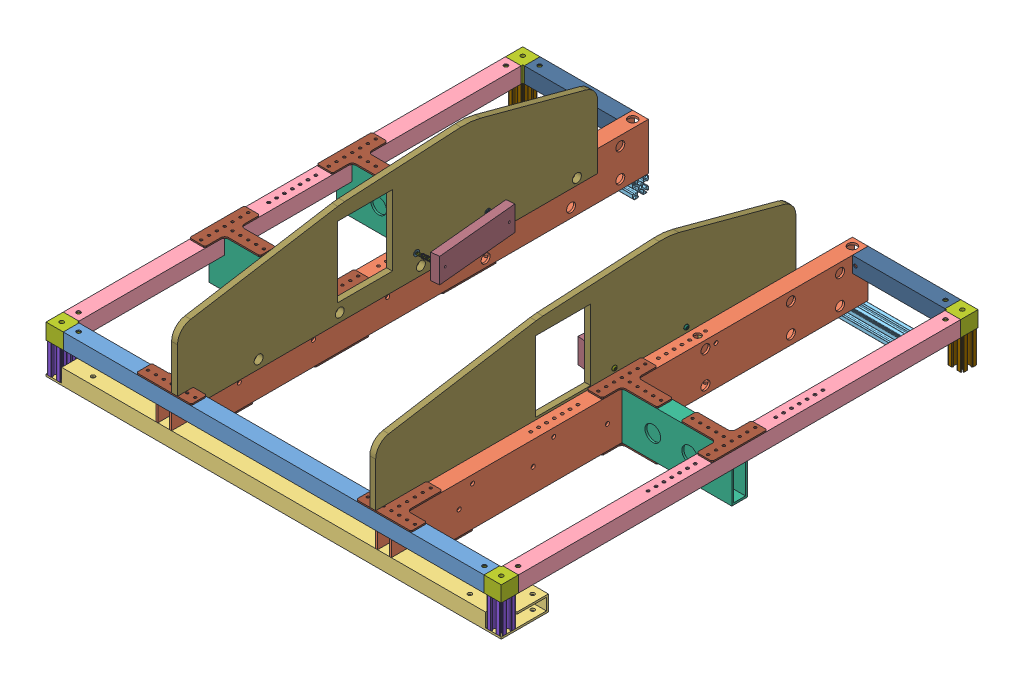
SolidWorks assembly Bumper Frame, configuration Default. Lengths in mm.
Overall size (736.6 251.87 771.42).
53 component instances, 18 part files, 107 mates.
Components (placement in the parent):
- 1x1x26.8 box channel for bumpers-2: 1x1x26.8 box channel for bumpers [Default] at (0 63.5 372.999) x (0 0 1) z (-1 0 0) size (25.4 25.4 680.72)
- 1x3x29.37 Boxtubing-1: 1x3x29.37 Boxtubing [Default] at (-177.8 38.1 0) x (-1 0 0) z (0 0 -1) size (25.4 76.2 771.4)
- 1x3x29.37 Boxtubing-2: 1x3x29.37 Boxtubing [Default] at (177.8 38.1 0) x (-1 0 0) z (0 0 -1) size (25.4 76.2 771.4)
- 1x3 Boxtubing-2: 1x3 Boxtubing [Default] at (0 12.7 347.599) x (0 -1 0) z (-1 0 0) size (25.4 76.2 736.6)
- 1x1x29.27in bumper box tubing-1: 1x1x29.27in bumper box tubing [Default] at (355.6 63.5 0) size (25.4 25.4 715.52)
- 1x1x29.27in bumper box tubing-2: 1x1x29.27in bumper box tubing [Default] at (-355.6 63.5 0) x (-1 0 0) z (0 0 -1) size (25.4 25.4 715.52)
- 1x1x5.00 Extrusion-3: 1x1x5.00 Extrusion [Default] at (228.6 -12.7 -372.999) x (0 0 1) z (-1 0 0) size (25.4 25.4 127)
- 1x1x5.00 Extrusion-2: 1x1x5.00 Extrusion [Default] at (-228.6 -12.7 -372.999) x (0 0 -1) z (1 0 0) size (25.4 25.4 127)
- 1x3x6 Boxtubing-2: 1x3x6 Boxtubing [Default] at (279.4 38.1 0) x (0 0 1) z (-1 0 0) size (25.4 76.2 177.8)
- 1x3x6 Boxtubing-6: 1x3x6 Boxtubing [Default] at (-279.4 38.1 109.2945) x (0 0 -1) z (1 0 0) size (25.4 76.2 177.8)
- 1x3x6 Boxtubing-7: 1x3x6 Boxtubing [Default] at (-279.4 38.1 -97.0932) x (0 0 -1) z (1 0 0) size (25.4 76.2 177.8)
- bumper box tubing connector-1: bumper box tubing connector [Default] at (342.9 63.5 360.299) x (0 0 -1) z (0 1 0) size (50.8 50.8 25.4)
- bumper box tubing connector-2: bumper box tubing connector [Default] at (-342.9 63.5 360.299) x (0 0 -1) z (0 -1 0) size (50.8 50.8 25.4)
- bumper box tubing connector-3: bumper box tubing connector [Default] at (342.9 63.5 -360.299) x (-1 0 0) z (0 1 0) size (50.8 50.8 25.4)
- bumper box tubing connector-4: bumper box tubing connector [Default] at (-342.9 63.5 -360.299) x (1 0 0) z (0 -1 0) size (50.8 50.8 25.4)
- Part1^Bumper Frame-1: Part1^Bumper Frame [Default] at origin (virtual)
- 1x1x2.88 Extrusion Real-3: 1x1x2.88 Extrusion Real [Default] at (-355.6 26.8297 372.999) x (1 0 0) z (0 1 0) size (25.4 25.4 47.94)
- 1x1x2.88 Extrusion Real-2: 1x1x2.88 Extrusion Real [Default] at (355.6 26.8297 372.999) x (1 0 0) z (0 -1 0) size (25.4 25.4 47.94)
- 1x1x2.01 Extrusion Real-1: 1x1x2.01 Extrusion Real [Default] at (-355.6 25.2422 -372.999) x (1 0 0) z (0 1 0) size (25.4 25.4 51.12)
- 1x1x2.01 Extrusion Real-2: 1x1x2.01 Extrusion Real [Default] at (355.6 25.2422 -372.999) x (1 0 0) z (0 -1 0) size (25.4 25.4 51.12)
- 1x1x5.9 boxtubing-2: 1x1x5.9 boxtubing [Default] at (265.43 63.4746 -373.0244) x (0 0 1) z (-1 0 0) size (25.4 25.4 149.86)
- 1x1x5.9 boxtubing-3: 1x1x5.9 boxtubing [Default] at (-265.43 63.5254 -373.0244) x (0 0 1) z (1 0 0) size (25.4 25.4 149.86)
- T Gusset Connector thing-2: T Gusset Connector thing [Default] at (-190.5 78.486 -97.0932) x (0 0 -1) z (0 -1 0) size (88.9 82.55 2.29)
- T Gusset Connector thing-3: T Gusset Connector thing [Default] at (-342.9 78.486 -97.0932) x (0 0 1) z (0 -1 0) size (88.9 82.55 2.29)
- T Gusset Connector thing-4: T Gusset Connector thing [Default] at (-342.9 78.486 109.2945) x (0 0 1) z (0 -1 0) size (88.9 82.55 2.29)
- T Gusset Connector thing-5: T Gusset Connector thing [Default] at (-190.5 78.486 109.2945) x (0 0 -1) z (0 -1 0) size (88.9 82.55 2.29)
- T Gusset Connector thing-6: T Gusset Connector thing [Default] at (190.5 76.2 0) x (0 0 -1) z (0 1 0) size (88.9 82.55 2.29)
- T Gusset Connector thing-7: T Gusset Connector thing [Default] at (342.9 78.486 0) x (0 0 -1) z (0 -1 0) size (88.9 82.55 2.29)
- T Gusset Connector thing-8: T Gusset Connector thing [Default] at (-177.8 78.486 360.299) x (1 0 0) z (0 -1 0) size (88.9 82.55 2.29)
- T Gusset Connector thing-9: T Gusset Connector thing [Default] at (177.8 76.2 360.299) x (-1 0 0) z (0 1 0) size (88.9 82.55 2.29)
- T Gusset Connector thing-10: T Gusset Connector thing [Default] at (190.5 0 0) x (0 0 1) z (0 -1 0) size (88.9 82.55 2.29)
- T Gusset Connector thing-11: T Gusset Connector thing [Default] at (-190.5 0 109.2945) x (0 0 -1) z (0 -1 0) size (88.9 82.55 2.29)
- T Gusset Connector thing-12: T Gusset Connector thing [Default] at (-190.5 0 -97.0932) x (0 0 -1) z (0 -1 0) size (88.9 82.55 2.29)
- T Gusset Connector thing-13: T Gusset Connector thing [Default] at (177.8 -2.286 309.499) x (-1 0 0) z (0 1 0) size (88.9 82.55 2.29)
- T Gusset Connector thing-14: T Gusset Connector thing [Default] at (-177.8 -2.286 309.499) x (-1 0 0) z (0 1 0) size (88.9 82.55 2.29)
- Polycarb Big Piece-1: Polycarb Big Piece [Default] at (-160.3375 50.8 45.699) x (0 0 -1) z (1 0 0) size (680 175.67 9.53)
- Polycarb Big Piece-2: Polycarb Big Piece [Default] at (160.3375 50.8 45.699) x (0 0 -1) z (1 0 0) size (680 175.67 9.53)
- BallWedgeAssembly-1: BallWedgeAssembly [Default] at (-124.8444 86.1 -61.4487) x (0.094074 0 0.995565) z (-0.995565 0 0.094074) size (135 40 55.6) (flexible)
  - BallWedge-1: BallWedge [Default] at origin size (135 40 13.26)
  - M4WasherFlat-1: M4WasherFlat [Default] at (-57.4247 0 24.6377) x (0.935485 0.342132 0.088397) z (0.340615 -0.939652 0.032186) size (9 0.8 9)
  - M4WasherFlat-2: M4WasherFlat [Default] at (57.4247 0 36.2937) x (0.991573 0.089461 0.093697) z (-0.089064 0.99599 -0.008416) size (9 0.8 9)
  - M4x30pan-4: M4x30pan [92095A198] at (-57.5 0 38.83) x (-0.45772 0.889096 0) z (0 0 1) size (7.6 7.6 32.66)
  - M4x40pan-4: M4x40pan [92095A200] at (57.5 0 48.83) x (0.675672 0.737202 0) z (0 0 1) size (7.6 7.6 42.77)
  - Spring-1: Spring [9657K284] at (-57.5 0 24.7164) x (-0.189743 -0.981834 0) z (0 0 1) size (6.28 6.36 19.34)
  - Spring-2: Spring [9657K284] at (57.5 0 27.478) x (0.996205 -0.087034 0) z (0 0 1) size (6.28 6.36 19.34)
- BallWedgeAssembly-2: BallWedgeAssembly [Default] at (124.8444 86.1 -61.4487) x (-0.094074 0 0.995565) z (0.995565 0 0.094074) size (135 40 55.6) (flexible)
  - BallWedge-1: BallWedge [Default] at origin size (135 40 13.26)
  - M4WasherFlat-1: M4WasherFlat [Default] at (-57.4247 0 24.6377) x (0.988649 -0.117664 0.093421) z (-0.117142 -0.993053 -0.011069) size (9 0.8 9)
  - M4WasherFlat-2: M4WasherFlat [Default] at (57.4247 0 36.2937) x (0.992414 0.079499 0.093776) z (-0.079146 0.996835 -0.007479) size (9 0.8 9)
  - M4x30pan-4: M4x30pan [92095A198] at (-57.5 0 38.83) x (-0.583863 0.811852 0) z (0 0 1) size (7.6 7.6 32.66)
  - M4x40pan-4: M4x40pan [92095A200] at (57.5 0 48.83) x (0.675672 0.737202 0) z (0 0 1) size (7.6 7.6 42.77)
  - Spring-1: Spring [9657K284] at (-57.5 0 24.601) x (-0.109202 -0.99402 0) z (0 0 1) size (6.28 6.36 19.34)
  - Spring-2: Spring [9657K284] at (57.5 0 26.6923) x (0.994166 -0.107862 0) z (0 0 1) size (6.28 6.36 19.34)
Mates (geometry in assembly coordinates):
- Coincident286: coincident anti-aligned: line of 1x3x29.37 Boxtubing-2 through (165.1 0 -385.699) axis (0 0 1); plane of 1x1x5.00 Extrusion-3 through (165.1 -0.75 -363.2396) normal (-1 0 0)
- Coincident288: coincident anti-aligned: line of 1x3x29.37 Boxtubing-2 through (165.1 0 -385.699) axis (0 1 0); plane of 1x1x5.00 Extrusion-3 through (165.1 -7.9893 -385.699) normal (0 0 -1)
- Coincident291: coincident aligned: line of 1x1x29.27in bumper box tubing-1 through (368.3 50.8 -357.759) axis (0 1 0); line of bumper box tubing connector-3 through (368.3 50.8 -357.759) axis (0 1 0)
- Coincident292: coincident aligned: line of 1x1x29.27in bumper box tubing-1 through (368.3 76.2 -357.759) axis (-1 0 0); line of bumper box tubing connector-3 through (368.3 76.2 -357.759) axis (-1 0 0)
- Coincident293: coincident anti-aligned: line of 1x1x29.27in bumper box tubing-2 through (-342.9 76.2 -357.759) axis (0 -1 0); line of bumper box tubing connector-4 through (-342.9 50.8 -357.759) axis (0 1 0)
- Coincident295: coincident anti-aligned: line of 1x1x29.27in bumper box tubing-2 through (-368.3 76.2 -357.759) axis (1 0 0); line of bumper box tubing connector-4 through (-342.9 76.2 -357.759) axis (-1 0 0)
- Coincident296: coincident anti-aligned: line of bumper box tubing connector-1 through (368.3 76.2 357.759) axis (0 -1 0); line of 1x1x29.27in bumper box tubing-1 through (368.3 50.8 357.759) axis (0 1 0)
- Coincident297: coincident anti-aligned: line of bumper box tubing connector-1 through (342.9 76.2 357.759) axis (1 0 0); line of 1x1x29.27in bumper box tubing-1 through (368.3 76.2 357.759) axis (-1 0 0)
- Coincident298: coincident aligned: line of bumper box tubing connector-1 through (340.36 50.8 385.699) axis (0 1 0); line of 1x1x26.8 box channel for bumpers-2 through (340.36 50.8 385.699) axis (0 1 0)
- Coincident299: coincident aligned: line of bumper box tubing connector-1 through (340.36 76.2 385.699) axis (0 0 -1); line of 1x1x26.8 box channel for bumpers-2 through (340.36 76.2 385.699) axis (0 0 -1)
- Coincident300: coincident anti-aligned: line of 1x1x26.8 box channel for bumpers-2 through (-340.36 76.2 385.699) axis (0 0 -1); line of bumper box tubing connector-2 through (-340.36 76.2 360.299) axis (0 0 1)
- Coincident301: coincident anti-aligned: line of 1x1x26.8 box channel for bumpers-2 through (-340.36 50.8 385.699) axis (0 1 0); line of bumper box tubing connector-2 through (-340.36 76.2 385.699) axis (0 -1 0)
- Coincident310: coincident aligned: line of bumper box tubing connector-2 through (-368.3 76.2 357.759) axis (1 0 0); line of 1x1x29.27in bumper box tubing-2 through (-368.3 76.2 357.759) axis (1 0 0)
- Coincident311: coincident aligned: line of bumper box tubing connector-2 through (-368.3 50.8 357.759) axis (0 1 0); line of 1x1x29.27in bumper box tubing-2 through (-368.3 50.8 357.759) axis (0 1 0)
- Coincident313: coincident anti-aligned: plane of 1x3x29.37 Boxtubing-2; plane of 1x3x6 Boxtubing-2 through (279.4 38.1 0) normal (0 0 1)
- Coincident314: coincident aligned: plane of 1x3x29.37 Boxtubing-1; plane of 1x3x6 Boxtubing-6 through (-279.4 38.1 109.2945) normal (0 0 -1)
- Coincident315: coincident aligned: plane of 1x3x29.37 Boxtubing-1; plane of 1x3x6 Boxtubing-7 through (-279.4 38.1 -97.0932) normal (0 0 -1)
- Coincident316: coincident aligned: line of 1x3x29.37 Boxtubing-1 through (-190.5 76.2 -385.699) axis (0 0 1); line of 1x3x6 Boxtubing-7 through (-190.5 76.2 -94.712) axis (0 0 1)
- Coincident317: coincident aligned: line of 1x3x29.37 Boxtubing-1 through (-190.5 76.2 -385.699) axis (0 0 1); line of 1x3x6 Boxtubing-6 through (-190.5 76.2 111.6757) axis (0 0 1)
- Coincident318: coincident aligned: plane of 1x3x29.37 Boxtubing-2 through (190.5 76.2 -385.699) normal (0 1 0); plane of 1x3x6 Boxtubing-2 through (190.5 76.2 -12.7) normal (0 1 0)
- Coincident319: coincident aligned: plane of 1x3x29.37 Boxtubing-2 through (177.8 38.1 0) normal (-1 0 0); plane of 1x1x26.8 box channel for bumpers-2
- Coincident320: coincident aligned: plane of 1x3x29.37 Boxtubing-1 through (-177.8 38.1 0) normal (-1 0 0); plane of 1x1x26.8 box channel for bumpers-2
- Coincident324: coincident anti-aligned: line of 1x3x29.37 Boxtubing-2 through (190.5 76.2 -385.699) axis (0 0 1); line of 1x3x6 Boxtubing-2 through (190.5 76.2 12.7) axis (0 0 -1)
- Coincident325: coincident aligned: plane of 1x3 Boxtubing-2 through (0 12.7 347.599) normal (-1 0 0); plane of 1x1x26.8 box channel for bumpers-2 through (0 63.5 372.999) normal (-1 0 0)
- Coincident326: coincident aligned: plane of 1x3 Boxtubing-2 through (-368.3 25.4 385.699) normal (0 0 1); plane of 1x1x26.8 box channel for bumpers-2 through (-340.36 50.8 385.699) normal (0 0 1)
- Coincident327: coincident aligned: plane of 1x3x29.37 Boxtubing-1 through (-165.1 0 -385.699) normal (0 -1 0); plane of 1x3 Boxtubing-2 through (-368.3 0 309.499) normal (0 -1 0)
- Coincident332: coincident aligned: plane of 1x3x29.37 Boxtubing-2 through (190.5 76.2 -385.699) normal (0 1 0); plane of 1x1x26.8 box channel for bumpers-2 through (-340.36 76.2 360.299) normal (0 1 0)
- Coincident333: coincident aligned: plane of 1x3x29.37 Boxtubing-1 through (-165.1 76.2 -385.699) normal (0 1 0); plane of 1x1x26.8 box channel for bumpers-2 through (-340.36 76.2 360.299) normal (0 1 0)
- Coincident334: coincident aligned: plane of 1x3x29.37 Boxtubing-1 through (-177.8 38.1 385.699) normal (0 0 1); plane of 1x1x26.8 box channel for bumpers-2 through (-340.36 50.8 385.699) normal (0 0 1)
- Coincident335: coincident aligned: plane of 1x3x29.37 Boxtubing-2 through (177.8 38.1 385.699) normal (0 0 1); plane of 1x1x26.8 box channel for bumpers-2 through (-340.36 50.8 385.699) normal (0 0 1)
- Coincident336: coincident anti-aligned: plane of 1x1x26.8 box channel for bumpers-2 through (0 63.5 372.999) normal (-1 0 0); plane of assembly through (0 0 0) normal (1 0 0)
- Coincident337: coincident anti-aligned: plane of 1x3x29.37 Boxtubing-1 through (-177.8 38.1 0) normal (0 0 -1); plane of assembly through (0 0 0) normal (0 0 1)
- Coincident338: coincident anti-aligned: plane of 1x3 Boxtubing-2 through (-368.3 0 309.499) normal (0 -1 0); plane of assembly through (0 0 0) normal (0 1 0)
- Concentric1: concentric aligned: cylinder of bumper box tubing connector-2 through (-355.6 76.2 372.999) axis (0 -1 0) radius 3.3; cylinder of 1x1x2.88 Extrusion Real-3 through (-355.6 50.8 372.999) axis (0 -1 0) radius 2.08
- Coincident339: coincident anti-aligned: plane of bumper box tubing connector-2 through (-342.9 50.8 360.299) normal (0 -1 0); line of 1x1x2.88 Extrusion Real-3 through (-360.3107 50.8 385.699) axis (-1 0 0)
- Parallel10: parallel aligned: plane of bumper box tubing connector-2 through (-368.3 50.8 385.699) normal (0 0 1); plane of 1x1x2.88 Extrusion Real-3 through (-360.3107 50.8 385.699) normal (0 0 1)
- Concentric2: concentric aligned: cylinder of bumper box tubing connector-1 through (355.6 50.8 372.999) axis (0 1 0) radius 3.3; cylinder of 1x1x2.88 Extrusion Real-2 through (355.6 2.8594 372.999) axis (0 1 0) radius 2.08
- Coincident341: coincident anti-aligned: plane of bumper box tubing connector-1 through (342.9 50.8 360.299) normal (0 -1 0); line of 1x1x2.88 Extrusion Real-2 through (368.3 50.8 382.7584) axis (0 0 -1)
- Parallel11: parallel aligned: plane of bumper box tubing connector-1 through (368.3 76.2 385.699) normal (1 0 0); plane of 1x1x2.88 Extrusion Real-2 through (368.3 2.8594 382.7584) normal (1 0 0)
- Concentric3: concentric aligned: cylinder of bumper box tubing connector-3 through (355.6 50.8 -372.999) axis (0 1 0) radius 3.3; cylinder of 1x1x2.01 Extrusion Real-2 through (355.6 -0.3156 -372.999) axis (0 1 0) radius 2.08
- Coincident343: coincident anti-aligned: plane of bumper box tubing connector-3 through (342.9 50.8 -360.299) normal (0 -1 0); line of 1x1x2.01 Extrusion Real-2 through (365.3594 50.8 -385.699) axis (-1 0 0)
- Parallel12: parallel aligned: plane of bumper box tubing connector-3 through (368.3 76.2 -385.699) normal (0 0 -1); plane of 1x1x2.01 Extrusion Real-2 through (365.3594 -0.3156 -385.699) normal (0 0 -1)
- Concentric4: concentric aligned: cylinder of bumper box tubing connector-4 through (-355.6 76.2 -372.999) axis (0 -1 0) radius 3.3; cylinder of 1x1x2.01 Extrusion Real-1 through (-355.6 50.8 -372.999) axis (0 -1 0) radius 2.08
- Coincident345: coincident anti-aligned: plane of bumper box tubing connector-4 through (-342.9 50.8 -360.299) normal (0 -1 0); plane of 1x1x2.01 Extrusion Real-1 through (-345.8406 50.8 -384.949) normal (0 1 0)
- Parallel13: parallel aligned: plane of bumper box tubing connector-4 through (-368.3 50.8 -385.699) normal (0 0 -1); plane of 1x1x2.01 Extrusion Real-1 through (-365.3594 50.8 -385.699) normal (0 0 -1)
- Coincident347: coincident anti-aligned: plane of bumper box tubing connector-3 through (340.36 63.5 -360.299) normal (-1 0 0); plane of 1x1x5.9 boxtubing-2 through (340.36 63.4746 -373.0244) normal (1 0 0)
- Coincident348: coincident anti-aligned: plane of bumper box tubing connector-3 through (340.36 74.5871 -384.0861) normal (0 1 0); plane of 1x1x5.9 boxtubing-2 through (190.5 74.5871 -385.7244) normal (0 -1 0)
- Coincident349: coincident anti-aligned: plane of bumper box tubing connector-3 through (340.36 74.5871 -361.9119) normal (0 0 1); plane of 1x1x5.9 boxtubing-2 through (190.5 50.7746 -361.9119) normal (0 0 -1)
- Coincident350: coincident anti-aligned: plane of bumper box tubing connector-4 through (-340.36 63.5 -360.299) normal (1 0 0); plane of 1x1x5.9 boxtubing-3 through (-340.36 63.5254 -373.0244) normal (-1 0 0)
- Coincident351: coincident anti-aligned: plane of bumper box tubing connector-4 through (-340.36 52.4129 -361.9119) normal (0 0 1); plane of 1x1x5.9 boxtubing-3 through (-190.5 76.2254 -361.9119) normal (0 0 -1)
- Coincident352: coincident anti-aligned: plane of bumper box tubing connector-4 through (-340.36 52.4129 -384.0861) normal (0 -1 0); plane of 1x1x5.9 boxtubing-3 through (-190.5 52.4129 -385.7244) normal (0 1 0)
- Coincident359: coincident anti-aligned: plane of 1x3x6 Boxtubing-7 through (-190.5 76.2 -84.3932) normal (0 1 0); plane of T Gusset Connector thing-2 through (-196.85 76.2 -116.1432) normal (0 -1 0)
- Coincident360: coincident aligned: plane of 1x3x6 Boxtubing-7 through (-190.5 0 -84.3932) normal (0 0 1); plane of T Gusset Connector thing-2 through (-196.85 78.486 -84.3932) normal (0 0 1)
- Coincident361: coincident aligned: plane of 1x3x29.37 Boxtubing-1 through (-190.5 0 -385.699) normal (-1 0 0); plane of T Gusset Connector thing-2 through (-190.5 78.486 -54.8022) normal (-1 0 0)
- Coincident362: coincident anti-aligned: plane of 1x3x6 Boxtubing-7 through (-190.5 76.2 -84.3932) normal (0 1 0); plane of T Gusset Connector thing-3 through (-336.55 76.2 -78.0432) normal (0 -1 0)
- Coincident363: coincident aligned: plane of 1x3x6 Boxtubing-7 through (-190.5 0 -109.7932) normal (0 0 -1); plane of T Gusset Connector thing-3 through (-336.55 78.486 -109.7932) normal (0 0 -1)
- Coincident364: coincident aligned: plane of 1x1x29.27in bumper box tubing-2 through (-342.9 50.8 -357.759) normal (1 0 0); plane of T Gusset Connector thing-3 through (-342.9 78.486 -139.3842) normal (1 0 0)
- Coincident365: coincident anti-aligned: plane of 1x3x6 Boxtubing-6 through (-190.5 76.2 121.9945) normal (0 1 0); plane of T Gusset Connector thing-4 through (-336.55 76.2 128.3445) normal (0 -1 0)
- Coincident366: coincident aligned: plane of 1x3x6 Boxtubing-6 through (-190.5 0 121.9945) normal (0 0 1); plane of T Gusset Connector thing-4 through (-287.909 78.486 121.9945) normal (0 0 1)
- Coincident367: coincident aligned: plane of 1x1x29.27in bumper box tubing-2 through (-342.9 50.8 -357.759) normal (1 0 0); plane of T Gusset Connector thing-4 through (-342.9 78.486 128.3445) normal (1 0 0)
- Coincident370: coincident aligned: plane of 1x3x29.37 Boxtubing-1 through (-190.5 0 -385.699) normal (-1 0 0); plane of T Gusset Connector thing-5 through (-190.5 78.486 151.5855) normal (-1 0 0)
- Coincident372: coincident aligned: plane of 1x3x6 Boxtubing-6 through (-190.5 0 96.5945) normal (0 0 -1); plane of T Gusset Connector thing-5 through (-245.491 78.486 96.5945) normal (0 0 -1)
- Coincident373: coincident anti-aligned: plane of 1x3x6 Boxtubing-6 through (-190.5 76.2 121.9945) normal (0 1 0); plane of T Gusset Connector thing-5 through (-196.85 76.2 90.2445) normal (0 -1 0)
- Coincident374: coincident anti-aligned: plane of 1x3x6 Boxtubing-2 through (190.5 76.2 -12.7) normal (0 1 0); plane of T Gusset Connector thing-6 through (196.85 76.2 -19.05) normal (0 -1 0)
- Coincident375: coincident aligned: plane of 1x3x6 Boxtubing-2 through (190.5 0 12.7) normal (0 0 1); plane of T Gusset Connector thing-6 through (196.85 76.2 12.7) normal (0 0 1)
- Coincident376: coincident aligned: plane of 1x3x29.37 Boxtubing-2 through (190.5 0 -385.699) normal (1 0 0); plane of T Gusset Connector thing-6 through (190.5 76.2 42.291) normal (1 0 0)
- Coincident377: coincident anti-aligned: plane of 1x3x6 Boxtubing-2 through (190.5 76.2 -12.7) normal (0 1 0); plane of T Gusset Connector thing-7 through (336.55 76.2 -19.05) normal (0 -1 0)
- Coincident378: coincident aligned: plane of 1x3x6 Boxtubing-2 through (190.5 0 12.7) normal (0 0 1); plane of T Gusset Connector thing-7 through (336.55 78.486 12.7) normal (0 0 1)
- Coincident379: coincident aligned: plane of 1x1x29.27in bumper box tubing-1 through (342.9 50.8 357.759) normal (-1 0 0); plane of T Gusset Connector thing-7 through (342.9 78.486 42.291) normal (-1 0 0)
- Coincident380: coincident anti-aligned: plane of 1x3x29.37 Boxtubing-1 through (-165.1 76.2 -385.699) normal (0 1 0); plane of T Gusset Connector thing-8 through (-158.75 76.2 353.949) normal (0 -1 0)
- Coincident381: coincident aligned: plane of 1x1x26.8 box channel for bumpers-2 through (-340.36 50.8 360.299) normal (0 0 -1); plane of T Gusset Connector thing-8 through (-220.091 78.486 360.299) normal (0 0 -1)
- Coincident382: coincident aligned: plane of 1x3x29.37 Boxtubing-1 through (-165.1 0 -385.699) normal (1 0 0); plane of T Gusset Connector thing-8 through (-165.1 78.486 305.308) normal (1 0 0)
- Coincident383: coincident anti-aligned: plane of 1x3x29.37 Boxtubing-2 through (190.5 76.2 -385.699) normal (0 1 0); plane of T Gusset Connector thing-9 through (158.75 76.2 353.949) normal (0 -1 0)
- Coincident384: coincident aligned: plane of 1x3x29.37 Boxtubing-2 through (190.5 0 -385.699) normal (1 0 0); plane of T Gusset Connector thing-9 through (190.5 76.2 353.949) normal (1 0 0)
- Coincident385: coincident aligned: plane of 1x1x26.8 box channel for bumpers-2 through (-340.36 50.8 360.299) normal (0 0 -1); plane of T Gusset Connector thing-9 through (220.091 76.2 360.299) normal (0 0 -1)
- Coincident386: coincident anti-aligned: plane of 1x3x6 Boxtubing-2 through (190.5 0 -12.7) normal (0 -1 0); plane of T Gusset Connector thing-10 through (196.85 0 19.05) normal (0 1 0)
- Coincident387: coincident aligned: plane of 1x3x29.37 Boxtubing-2 through (190.5 0 -385.699) normal (1 0 0); plane of T Gusset Connector thing-10 through (190.5 0 -42.291) normal (1 0 0)
- Coincident388: coincident aligned: plane of 1x3x6 Boxtubing-2 through (190.5 0 -12.7) normal (0 0 -1); plane of T Gusset Connector thing-10 through (196.85 0 -12.7) normal (0 0 -1)
- Coincident389: coincident anti-aligned: plane of 1x3x6 Boxtubing-6 through (-190.5 0 121.9945) normal (0 -1 0); plane of T Gusset Connector thing-11 through (-196.85 0 90.2445) normal (0 1 0)
- Coincident390: coincident aligned: plane of 1x3x29.37 Boxtubing-1 through (-190.5 0 -385.699) normal (-1 0 0); plane of T Gusset Connector thing-11 through (-190.5 0 90.2445) normal (-1 0 0)
- Coincident391: coincident aligned: plane of 1x3x6 Boxtubing-6 through (-190.5 0 96.5945) normal (0 0 -1); plane of T Gusset Connector thing-11 through (-245.491 0 96.5945) normal (0 0 -1)
- Coincident392: coincident anti-aligned: plane of 1x3x6 Boxtubing-7 through (-190.5 0 -84.3932) normal (0 -1 0); plane of T Gusset Connector thing-12 through (-196.85 0 -116.1432) normal (0 1 0)
- Coincident393: coincident aligned: plane of 1x3x29.37 Boxtubing-1 through (-190.5 0 -385.699) normal (-1 0 0); plane of T Gusset Connector thing-12 through (-190.5 0 -54.8022) normal (-1 0 0)
- Coincident394: coincident aligned: plane of 1x3x6 Boxtubing-7 through (-190.5 0 -109.7932) normal (0 0 -1); plane of T Gusset Connector thing-12 through (-245.491 0 -109.7932) normal (0 0 -1)
- Concentric5: concentric anti-aligned: cylinder of 1x3x29.37 Boxtubing-2 through (177.8 76.201 309.499) axis (0 -1 0) radius 2.3813; cylinder of T Gusset Connector thing-13 through (177.8 -2.286 309.499) axis (0 1 0) radius 2.0701
- Concentric6: concentric anti-aligned: cylinder of 1x3x29.37 Boxtubing-2 through (177.8 76.201 296.799) axis (0 -1 0) radius 2.3813; cylinder of T Gusset Connector thing-13 through (177.8 -2.286 296.799) axis (0 1 0) radius 2.0701
- Coincident395: coincident anti-aligned: plane of 1x3x29.37 Boxtubing-2 through (190.5 0 -385.699) normal (0 -1 0); plane of T Gusset Connector thing-13 through (158.75 0 303.149) normal (0 1 0)
- Coincident396: coincident anti-aligned: plane of 1x3x29.37 Boxtubing-1 through (-165.1 0 -385.699) normal (0 -1 0); plane of T Gusset Connector thing-14 through (-196.85 0 303.149) normal (0 1 0)
- Coincident397: coincident aligned: plane of 1x3x29.37 Boxtubing-1 through (-190.5 0 -385.699) normal (-1 0 0); plane of T Gusset Connector thing-14 through (-190.5 -2.286 254.508) normal (-1 0 0)
- Coincident399: coincident aligned: plane of 1x3 Boxtubing-2 through (-368.3 25.4 309.499) normal (0 0 -1); plane of T Gusset Connector thing-14 through (-196.85 -2.286 309.499) normal (0 0 -1)
- Coincident424: coincident aligned: plane of 1x3x29.37 Boxtubing-1 through (-165.1 0 -385.699) normal (1 0 0); plane of 1x1x5.00 Extrusion-2 through (-165.1 -0.75 -382.7584) normal (1 0 0)
- Coincident425: coincident anti-aligned: plane of 1x3x29.37 Boxtubing-1 through (-165.1 0 -385.699) normal (0 -1 0); plane of 1x1x5.00 Extrusion-2 through (-165.1 0 -377.7097) normal (0 1 0)
- Coincident426: coincident aligned: plane of 1x3x29.37 Boxtubing-1 through (-177.8 38.1 -385.699) normal (0 0 -1); plane of 1x1x5.00 Extrusion-2 through (-165.1 -2.9406 -385.699) normal (0 0 -1)
- Coincident427: coincident anti-aligned: plane of 1x3x29.37 Boxtubing-1 through (-165.1 0 -385.699) normal (1 0 0); plane of Polycarb Big Piece-1 through (-165.1 50.8 45.699) normal (-1 0 0)
- Coincident428: coincident anti-aligned: plane of 1x1x26.8 box channel for bumpers-2 through (-340.36 50.8 360.299) normal (0 0 -1); plane of Polycarb Big Piece-1 through (-165.1 50.8 360.299) normal (0 0 1)
- Coincident430: coincident anti-aligned: plane of 1x3x29.37 Boxtubing-2 through (165.1 0 -385.699) normal (-1 0 0); plane of Polycarb Big Piece-2 through (165.1 50.8 45.699) normal (1 0 0)
- Coincident431: coincident anti-aligned: plane of 1x1x26.8 box channel for bumpers-2 through (-340.36 50.8 360.299) normal (0 0 -1); plane of Polycarb Big Piece-2 through (155.575 50.8 360.299) normal (0 0 1)
- Parallel16: parallel aligned: plane of Polycarb Big Piece-1 through (-155.575 50.8 -294.301) normal (0 -1 0); plane of BallWedgeAssembly-1/BallWedge-1 through (-137.795 66.1 -128.0256) normal (0 -1 0)
- Distance5: distance = 17.78 mm: line of BallWedgeAssembly-1/BallWedge-1 through (-137.795 106.1 -128.0256) axis (0 -1 0); plane of Polycarb Big Piece-1 through (-155.575 50.8 45.699) normal (1 0 0)
- Distance6: distance = 30.48 mm: line of BallWedgeAssembly-1/BallWedge-1 through (-125.095 66.1 6.3757) axis (0 1 0); plane of Polycarb Big Piece-1 through (-155.575 50.8 45.699) normal (1 0 0)
- Coincident454: coincident: line of BallWedgeAssembly-2/M4x30pan-4 through (134.92 86.1 -118.2528) axis (0.995565 0 0.094074); point of assembly
- Distance7: distance = 17.78 mm: line of BallWedgeAssembly-2/BallWedge-1 through (137.795 66.1 -128.0256) axis (0 1 0); plane of Polycarb Big Piece-2 through (155.575 50.8 45.699) normal (-1 0 0)
- Parallel17: parallel aligned: plane of Polycarb Big Piece-2 through (165.1 50.8 -294.301) normal (0 -1 0); plane of BallWedgeAssembly-2/BallWedge-1 through (137.795 66.1 -128.0256) normal (0 -1 0)
- Distance8: distance = 30.48 mm: line of BallWedgeAssembly-2/BallWedge-1 through (125.095 106.1 6.3757) axis (0 -1 0); plane of Polycarb Big Piece-2 through (155.575 50.8 45.699) normal (-1 0 0)
- Coincident455: coincident anti-aligned: plane of Polycarb Big Piece-1 through (-155.575 50.8 45.699) normal (1 0 0); plane of BallWedgeAssembly-1/M4WasherFlat-1 through (-155.575 86.1 -116.301) normal (-1 0 0)
- Coincident456: coincident anti-aligned: plane of Polycarb Big Piece-2 through (155.575 50.8 45.699) normal (-1 0 0); plane of BallWedgeAssembly-2/M4WasherFlat-1 through (155.575 86.1 -116.301) normal (1 0 0)
- Coincident457: coincident: line of BallWedgeAssembly-1/M4x30pan-4 through (-134.92 86.1 -118.2528) axis (-0.995565 0 0.094074)
